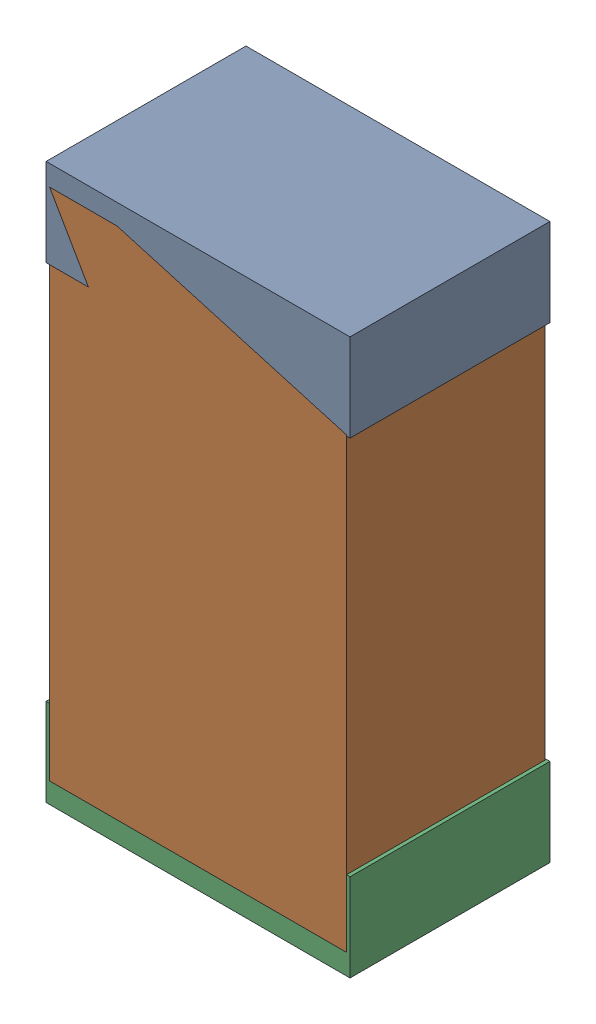
SolidWorks assembly R4, configuration Default. Lengths in mm.
Overall size (1.3 2.38 0.85).
6 component instances, 2 part files, 0 mates.
Components (placement in the parent):
- 402662288-1: 402662288 [Default] at (151.638 103.616 -1.9574) size (1.3 0.38 0.85)
  - Extruded_16-1: Extruded_16 [Default] at origin size (1.3 0.38 0.85)
- 402662416-1: 402662416 [Default] at (151.638 102.616 -1.9524) size (1.27 2.2 0.85)
  - Extruded_17-1: Extruded_17 [Default] at origin size (1.27 2.2 0.85)
- 402662288-2: 402662288 [Default] at (151.638 101.616 -1.9574) size (1.3 0.38 0.85)
  - Extruded_16-1: Extruded_16 [Default] at origin size (1.3 0.38 0.85)
